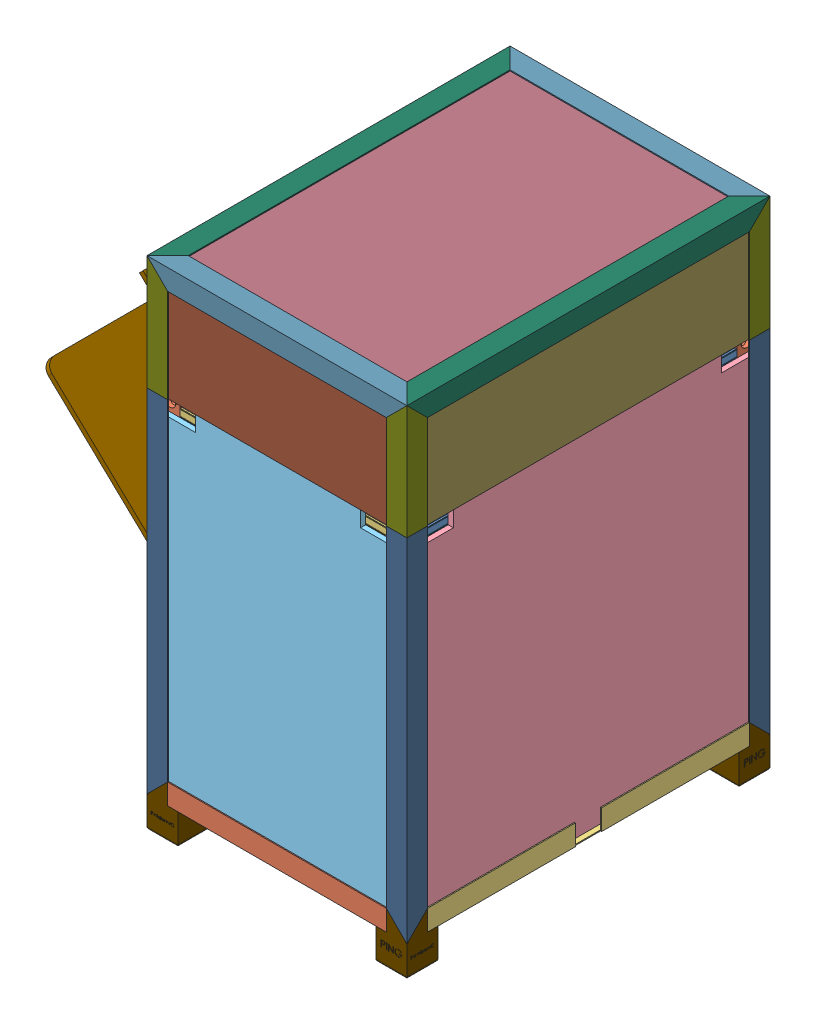
SolidWorks assembly carcasse, configuration Défaut. Lengths in mm.
Overall size (850.58 964 704).
62 component instances, 21 part files, 73 mates.
Components (placement in the parent):
- cadre_600x300mm-1: cadre_600x300mm [Défaut] at (-215.194 -19.8636 -400) size (480 40 680)
  - prof_40x40x600mm-1: prof_40x40x600mm [Défaut] at (-14.8937 4.0689 600) size (40 40 600)
  - Rexroth-Default-1: Rexroth-Default [Default] at (-14.8937 24.0689 720) x (0 -1 0) z (-1 0 0) size (40 40 40)
  - prof_40x40x600mm-3: prof_40x40x600mm [Défaut] at (425.1063 4.0689 600) size (40 40 600)
  - Rexroth-Default-3: Rexroth-Default [Default] at (-14.8937 24.0689 80) x (0 -1 0) z (0 0 -1) size (40 40 40)
  - Rexroth-Default-4: Rexroth-Default [Default] at (425.1063 24.0689 80) x (0 -1 0) z (1 0 0) size (40 40 40)
  - Rexroth-Default-5: Rexroth-Default [Default] at (425.1063 24.0689 720) x (0 -1 0) z (0 0 1) size (40 40 40)
  - prof_40x40x300mm-1: prof_40x40x300mm [Défaut] at (105.1063 4.0689 720) x (0 0 1) z (-1 0 0) size (40 40 400)
  - prof_40x40x300mm-2: prof_40x40x300mm [Défaut] at (105.1063 4.0689 80) x (0 0 1) z (-1 0 0) size (40 40 400)
- prof_40x40x600mm-1: prof_40x40x600mm [Défaut] at (209.9123 104.2053 -320) x (1 0 0) z (0 -1 0) size (40 40 600)
- prof_40x40x600mm-2: prof_40x40x600mm [Défaut] at (209.9123 104.2053 320) x (1 0 0) z (0 -1 0) size (40 40 600)
- prof_40x40x600mm-3: prof_40x40x600mm [Défaut] at (-230.0877 104.2053 320) x (1 0 0) z (0 -1 0) size (40 40 600)
- prof_40x40x600mm-4: prof_40x40x600mm [Défaut] at (-230.0877 104.2053 -320) x (1 0 0) z (0 -1 0) size (40 40 600)
- cadre_600x300mm-2: cadre_600x300mm [Défaut] at (195.0186 628.2742 -400) x (-1 0 0) z (0 0 1) size (480 40 680)
  - prof_40x40x600mm-1: prof_40x40x600mm [Défaut] at (-14.8937 4.0689 600) size (40 40 600)
  - Rexroth-Default-1: Rexroth-Default [Default] at (-14.8937 24.0689 720) x (0 -1 0) z (-1 0 0) size (40 40 40)
  - prof_40x40x600mm-3: prof_40x40x600mm [Défaut] at (425.1063 4.0689 600) size (40 40 600)
  - Rexroth-Default-3: Rexroth-Default [Default] at (-14.8937 24.0689 80) x (0 -1 0) z (0 0 -1) size (40 40 40)
  - Rexroth-Default-4: Rexroth-Default [Default] at (425.1063 24.0689 80) x (0 -1 0) z (1 0 0) size (40 40 40)
  - Rexroth-Default-5: Rexroth-Default [Default] at (425.1063 24.0689 720) x (0 -1 0) z (0 0 1) size (40 40 40)
  - prof_40x40x300mm-1: prof_40x40x300mm [Défaut] at (105.1063 4.0689 720) x (0 0 1) z (-1 0 0) size (40 40 400)
  - prof_40x40x300mm-2: prof_40x40x300mm [Défaut] at (105.1063 4.0689 80) x (0 0 1) z (-1 0 0) size (40 40 400)
- plaque_acrylique_680x670-2: plaque_acrylique_680x670 [Défaut] at (229.9123 299.2053 0) x (0 0 -1) z (1 0 0) size (680 670 10)
- plaque_acrylique_380x670-1: plaque_acrylique_380x670 [Défaut] at (39.9123 299.2053 -350) size (480 670 10)
- plaque_acrylique_380x670-2: plaque_acrylique_380x670 [Défaut] at (39.9123 299.2053 340) size (480 670 10)
- plaque_acrylique_680x670_porte-1: plaque_acrylique_680x670_porte [Défaut] at (-260.0877 299.2053 0) x (0 0 -1) z (1 0 0) size (680 670 10)
- charniere-1: charniere [Défaut] at (-253.7309 154.2053 256.2875) x (0 0 1) z (0 -1 0) size (40 29.08 53.23)
  - axe charnière-1: axe charnière [Défaut] at (-76.2875 9.8568 0) size (40 5 5)
  - batant charnière-1: batant charnière [Défaut] at (-76.2875 10.1991 -17.6196) size (40 7 33.5)
  - batant charnière-2: batant charnière [Défaut] at (-36.2875 -2.6626 12.4029) x (-1 0 0) z (0 0.723942 -0.689861) size (40 7 33.5)
- charniere-2: charniere [Défaut] at (-253.7309 154.2053 -143.7125) x (0 0 1) z (0 -1 0) size (40 29.08 53.23)
  - axe charnière-1: axe charnière [Défaut] at (-76.2875 9.8568 0) size (40 5 5)
  - batant charnière-1: batant charnière [Défaut] at (-76.2875 10.1991 -17.6196) size (40 7 33.5)
  - batant charnière-2: batant charnière [Défaut] at (-36.2875 -2.6626 12.4029) x (-1 0 0) z (0 0.723942 -0.689861) size (40 7 33.5)
- porte-1: porte [Défaut] at (-366.1448 256.769 0) x (0 0 -1) z (0.689861 0.723942 0) size (480 480 10)
- eclisse_40x40x670_bisote_x1-1: eclisse_40x40x670_bisote_x1 [Défaut] at (-242.0877 -47.7947 -331.8864) size (40 682 40)
- eclisse_40x40x670_bisote_x1-2: eclisse_40x40x670_bisote_x1 [Défaut] at (-241.9741 -47.7947 332) x (0 0 -1) z (1 0 0) size (40 682 40)
- eclisse_40x40x670_bisote_x1-3: eclisse_40x40x670_bisote_x1 [Défaut] at (221.9123 -47.7947 331.8864) x (-1 0 0) z (0 0 -1) size (40 682 40)
- eclisse_40x40x670_bisote_x1-4: eclisse_40x40x670_bisote_x1 [Défaut] at (221.7986 -47.7947 -332) x (0 0 1) z (-1 0 0) size (40 682 40)
- couvercle-1: couvercle [Défaut] at (227.4119 747.9268 345) size (504 222 704)
  - plaque_acrylique_380x210-1: plaque_acrylique_380x210 [Défaut] at (-187.4996 -8.7215 -5) size (480 210 10)
  - plaque_acrylique_680x210-1: plaque_acrylique_680x210 [Défaut] at (2.5004 -8.7215 -345) x (0 0 -1) z (1 0 0) size (680 210 10)
  - plaque_acrylique_680x210-2: plaque_acrylique_680x210 [Défaut] at (-487.4996 -8.7215 -345) x (0 0 -1) z (1 0 0) size (680 210 10)
  - plaque_acrylique_380x210-2: plaque_acrylique_380x210 [Défaut] at (-187.4996 -8.7215 -695) size (480 210 10)
  - plaque_acrylique_380x680-1: plaque_acrylique_380x680 [Défaut] at (-187.4996 96.2785 -345) x (1 0 0) z (0 1 0) size (480 680 10)
  - eclisse_40x40x404_bisote_x2-1: eclisse_40x40x404_bisote_x2 [Défaut] at (14.5004 88.1649 -677) x (0 0 1) z (0 -1 0) size (40 504 40)
  - eclisse_40x40x704_bisote_x2-1: eclisse_40x40x704_bisote_x2 [Défaut] at (-5.6132 88.2785 -697) x (0 -1 0) z (-1 0 0) size (40 704 40)
  - eclisse_40x40x404_bisote_x2-2: eclisse_40x40x404_bisote_x2 [Défaut] at (-489.4996 88.1649 -13) x (0 0 -1) z (0 -1 0) size (40 504 40)
  - eclisse_40x40x704_bisote_x2-2: eclisse_40x40x704_bisote_x2 [Défaut] at (-469.4996 88.1649 -697) x (1 0 0) z (0 -1 0) size (40 704 40)
  - eclisse_40x40x222_bisote_x1-1: eclisse_40x40x222_bisote_x1 [Défaut] at (-469.386 108.2785 -677) x (0 0 1) z (1 0 0) size (40 222 40)
  - eclisse_40x40x222_bisote_x1-2: eclisse_40x40x222_bisote_x1 [Défaut] at (-5.4996 108.2785 -676.8864) x (-1 0 0) z (0 0 1) size (40 222 40)
  - eclisse_40x40x222_bisote_x1-3: eclisse_40x40x222_bisote_x1 [Défaut] at (-5.6132 108.2785 -13) x (0 0 -1) z (-1 0 0) size (40 222 40)
  - eclisse_40x40x222_bisote_x1-4: eclisse_40x40x222_bisote_x1 [Défaut] at (-469.4996 108.2785 -13.1136) x (1 0 0) z (0 0 -1) size (40 222 40)
- plaque_acrylique_bas_380x680-1: plaque_acrylique_bas_380x680 [Défaut] at (39.9123 -35.7947 0) x (1 0 0) z (0 -1 0) size (480 680 10)
- Pied-1: Pied [Défaut] at (181.9123 -47.7947 -292) x (-1 0 0) z (0 -1 0) size (60 60 100)
- Pied-2: Pied [Défaut] at (181.9123 -47.7947 292) x (0 0 -1) z (0 -1 0) size (60 60 100)
- Pied-3: Pied [Défaut] at (-202.0877 -47.7947 292) x (1 0 0) z (0 -1 0) size (60 60 100)
- Pied-4: Pied [Défaut] at (-202.0877 -47.7947 -292) x (0 0 1) z (0 -1 0) size (60 60 100)
- eclisse_bas_40x40x704-2: eclisse_bas_40x40x704 [Défaut] at (-242.0877 -27.681 312) x (1 0 0) z (0 1 0) size (40 624 40)
- eclisse_bas_40x40x404-1: eclisse_bas_40x40x404 [Défaut] at (-222.0877 -27.681 -332) x (0 0 1) z (0 1 0) size (40 424 40)
- eclisse_bas_40x40x404-2: eclisse_bas_40x40x404 [Défaut] at (201.9123 -27.681 332) x (0 0 -1) z (0 1 0) size (40 424 40)
- eclisse_bas_support_Z_40x40x704-1: eclisse_bas_support_Z_40x40x704 [Défaut] at (221.7986 -27.7947 312) x (0 1 0) z (-1 0 0) size (40 624 40)
Mates (geometry in assembly coordinates):
- Coïncidente1: coincident anti-aligned: plane of cadre_600x300mm-1/Rexroth-Default-3 through (-230.0877 4.2053 -320) normal (0 1 0); plane of prof_40x40x600mm-4 through (-213.0877 4.2053 -337) normal (0 -1 0)
- Coïncidente2: coincident anti-aligned: plane of cadre_600x300mm-1/Rexroth-Default-1 through (-230.0877 4.2053 320) normal (0 1 0); plane of prof_40x40x600mm-3 through (-213.0877 4.2053 303) normal (0 -1 0)
- Coïncidente3: coincident anti-aligned: plane of cadre_600x300mm-1/Rexroth-Default-5 through (209.9123 4.2053 320) normal (0 1 0); plane of prof_40x40x600mm-2 through (226.9123 4.2053 303) normal (0 -1 0)
- Coïncidente4: coincident anti-aligned: plane of cadre_600x300mm-1/Rexroth-Default-4 through (209.9123 4.2053 -320) normal (0 1 0); plane of prof_40x40x600mm-1 through (226.9123 4.2053 -337) normal (0 -1 0)
- Coïncidente5: coincident aligned: plane of cadre_600x300mm-1/Rexroth-Default-4 through (229.9123 -15.7947 -320) normal (1 0 0); plane of prof_40x40x600mm-1 through (229.9123 604.2053 -314) normal (1 0 0)
- Coïncidente6: coincident aligned: plane of cadre_600x300mm-1/Rexroth-Default-4 through (209.9123 -15.7947 -340) normal (0 0 -1); plane of prof_40x40x600mm-1 through (215.9123 604.2053 -340) normal (0 0 -1)
- Coïncidente7: coincident aligned: plane of cadre_600x300mm-1/Rexroth-Default-5 through (229.9123 -15.7947 320) normal (1 0 0); plane of prof_40x40x600mm-2 through (229.9123 604.2053 303) normal (1 0 0)
- Coïncidente8: coincident aligned: plane of cadre_600x300mm-1/Rexroth-Default-5 through (209.9123 -15.7947 340) normal (0 0 1); plane of prof_40x40x600mm-2 through (226.9123 604.2053 340) normal (0 0 1)
- Coïncidente9: coincident aligned: plane of cadre_600x300mm-1/Rexroth-Default-1 through (-230.0877 -15.7947 340) normal (0 0 1); plane of prof_40x40x600mm-3 through (-213.0877 604.2053 340) normal (0 0 1)
- Coïncidente10: coincident aligned: plane of cadre_600x300mm-1/Rexroth-Default-1 through (-250.0877 -15.7947 320) normal (-1 0 0); plane of prof_40x40x600mm-3 through (-250.0877 604.2053 337) normal (-1 0 0)
- Coïncidente11: coincident aligned: plane of cadre_600x300mm-1/Rexroth-Default-3 through (-250.0877 -15.7947 -320) normal (-1 0 0); plane of prof_40x40x600mm-4 through (-250.0877 604.2053 -303) normal (-1 0 0)
- Coïncidente12: coincident aligned: plane of cadre_600x300mm-1/Rexroth-Default-3 through (-230.0877 -15.7947 -340) normal (0 0 -1); plane of prof_40x40x600mm-4 through (-247.0877 604.2053 -340) normal (0 0 -1)
- Coïncidente13: coincident anti-aligned: plane of prof_40x40x600mm-1 through (226.9123 604.2053 -337) normal (0 1 0); plane of cadre_600x300mm-2/Rexroth-Default-3 through (209.9123 604.2053 -320) normal (0 -1 0)
- Coïncidente14: coincident aligned: plane of prof_40x40x600mm-3 through (-250.0877 604.2053 337) normal (-1 0 0); plane of cadre_600x300mm-2/Rexroth-Default-5 through (-250.0877 624.2053 320) normal (-1 0 0)
- Coïncidente15: coincident aligned: plane of prof_40x40x600mm-3 through (-236.0877 604.2053 340) normal (0 0 1); plane of cadre_600x300mm-2/Rexroth-Default-5 through (-230.0877 624.2053 340) normal (0 0 1)
- Coïncidente38: coincident anti-aligned: plane of cadre_600x300mm-2/prof_40x40x600mm-1 through (229.9123 630.2053 -300) normal (1 0 0); plane of plaque_acrylique_680x670-2 through (229.9123 299.2053 0) normal (-1 0 0)
- Coïncidente39: coincident aligned: plane of prof_40x40x600mm-2 through (226.9123 604.2053 340) normal (0 0 1); plane of plaque_acrylique_680x670-2 through (239.9123 634.2053 340) normal (0 0 1)
- Coïncidente40: coincident aligned: plane of cadre_600x300mm-1/prof_40x40x600mm-3 through (215.9123 -35.7947 -300) normal (0 -1 0); plane of plaque_acrylique_680x670-2 through (239.9123 -35.7947 340) normal (0 -1 0)
- Coïncidente41: coincident anti-aligned: plane of prof_40x40x600mm-3 through (-213.0877 604.2053 340) normal (0 0 1); plane of plaque_acrylique_380x670-2 through (39.9123 299.2053 340) normal (0 0 -1)
- Coïncidente42: coincident aligned: plane of cadre_600x300mm-2/Rexroth-Default-5 through (-250.0877 624.2053 320) normal (-1 0 0); plane of plaque_acrylique_380x670-2 through (-250.0877 634.2053 350) normal (-1 0 0)
- Coïncidente43: coincident aligned: plane of cadre_600x300mm-1/prof_40x40x300mm-1 through (189.9123 -35.7947 326) normal (0 -1 0); plane of plaque_acrylique_380x670-2 through (-250.0877 -35.7947 350) normal (0 -1 0)
- Coïncidente44: coincident aligned: plane of cadre_600x300mm-1/prof_40x40x300mm-2 through (189.9123 -35.7947 -337) normal (0 -1 0); plane of plaque_acrylique_380x670-1 through (-250.0877 -35.7947 -340) normal (0 -1 0)
- Coïncidente45: coincident aligned: plane of cadre_600x300mm-2/Rexroth-Default-4 through (-250.0877 624.2053 -320) normal (-1 0 0); plane of plaque_acrylique_380x670-1 through (-250.0877 634.2053 -340) normal (-1 0 0)
- Coïncidente46: coincident anti-aligned: plane of prof_40x40x600mm-4 through (-247.0877 604.2053 -340) normal (0 0 -1); plane of plaque_acrylique_380x670-1 through (39.9123 299.2053 -340) normal (0 0 1)
- Coïncidente48: coincident aligned: plane of cadre_600x300mm-2/Rexroth-Default-5 through (-230.0877 624.2053 340) normal (0 0 1); plane of plaque_acrylique_680x670_porte-1 through (-250.0877 634.2053 340) normal (0 0 1)
- Coïncidente50: coincident anti-aligned: plane of plaque_acrylique_680x670_porte-1 through (-260.0877 299.2053 0) normal (-1 0 0); plane of charniere-1/batant charnière-1 through (-260.0877 114.2053 220) normal (1 0 0)
- Coïncidente51: coincident anti-aligned: plane of plaque_acrylique_680x670_porte-1 through (-260.0877 299.2053 0) normal (-1 0 0); plane of charniere-2/batant charnière-1 through (-260.0877 114.2053 -180) normal (1 0 0)
- Distance4: distance = 20 mm anti-aligned: plane of charniere-2/batant charnière-1 through (-263.5877 154.2053 -220) normal (0 0 -1); plane of plaque_acrylique_680x670_porte-1 through (-260.0877 574.2053 -240) normal (0 0 1)
- Coïncidente54: coincident aligned: line of plaque_acrylique_680x670_porte-1 through (-260.0877 154.2053 220) axis (0 0 -1); line of charniere-2/batant charnière-1 through (-260.0877 154.2053 -180) axis (0 0 -1)
- Distance5: distance = 20 mm anti-aligned: plane of plaque_acrylique_680x670_porte-1 through (-260.0877 574.2053 240) normal (0 0 -1); plane of charniere-1/batant charnière-1 through (-263.5877 154.2053 220) normal (0 0 1)
- Coïncidente57: coincident aligned: line of plaque_acrylique_680x670_porte-1 through (-260.0877 154.2053 220) axis (0 0 -1); line of charniere-1/batant charnière-1 through (-260.0877 154.2053 220) axis (0 0 -1)
- Coïncidente62: coincident anti-aligned: plane of charniere-1/batant charnière-2 through (-290.1309 184.3336 180) normal (0.689861 0.723942 0); plane of porte-1 through (-586.947 467.1766 30) normal (-0.689861 -0.723942 0)
- Coïncidente63: coincident anti-aligned: line of charniere-1/batant charnière-2 through (-261.1732 156.7391 200) axis (0 0 1); line of porte-1 through (-261.1732 156.7391 220) axis (0 0 -1)
- Coïncidente64: coincident anti-aligned: plane of plaque_acrylique_680x670_porte-1 through (-260.0877 574.2053 240) normal (0 0 -1); plane of porte-1 through (-558.3301 453.7202 240) normal (0 0 1)
- Coïncidente65: coincident anti-aligned: plane of plaque_acrylique_380x670-1 through (39.9123 299.2053 -350) normal (0 0 -1); plane of eclisse_40x40x670_bisote_x1-1 through (-260.0877 634.2053 -350) normal (0 0 1)
- Coïncidente66: coincident anti-aligned: plane of plaque_acrylique_680x670_porte-1 through (-260.0877 299.2053 0) normal (-1 0 0); plane of eclisse_40x40x670_bisote_x1-1 through (-260.0877 634.2053 -350) normal (1 0 0)
- Coïncidente67: coincident aligned: plane of plaque_acrylique_680x670_porte-1 through (-250.0877 634.2053 340) normal (0 1 0); plane of eclisse_40x40x670_bisote_x1-1 through (-242.0877 634.2053 -331.8864) normal (0 1 0)
- Coïncidente68: coincident anti-aligned: plane of plaque_acrylique_680x670-2 through (239.9123 299.2053 0) normal (1 0 0); plane of eclisse_40x40x670_bisote_x1-4 through (239.9123 634.2053 -350) normal (-1 0 0)
- Coïncidente69: coincident anti-aligned: plane of plaque_acrylique_380x670-1 through (39.9123 299.2053 -350) normal (0 0 -1); plane of eclisse_40x40x670_bisote_x1-4 through (239.9123 634.2053 -350) normal (0 0 1)
- Coïncidente70: coincident aligned: plane of plaque_acrylique_380x670-1 through (-250.0877 634.2053 -340) normal (0 1 0); plane of eclisse_40x40x670_bisote_x1-4 through (221.7986 634.2053 -332) normal (0 1 0)
- Coïncidente71: coincident anti-aligned: plane of plaque_acrylique_380x670-2 through (39.9123 299.2053 350) normal (0 0 1); plane of eclisse_40x40x670_bisote_x1-2 through (-260.0877 634.2053 350) normal (0 0 -1)
- Coïncidente72: coincident anti-aligned: plane of plaque_acrylique_680x670_porte-1 through (-260.0877 299.2053 0) normal (-1 0 0); plane of eclisse_40x40x670_bisote_x1-2 through (-260.0877 634.2053 350) normal (1 0 0)
- Coïncidente73: coincident aligned: plane of plaque_acrylique_380x670-2 through (-250.0877 634.2053 350) normal (0 1 0); plane of eclisse_40x40x670_bisote_x1-2 through (-241.9741 634.2053 332) normal (0 1 0)
- Coïncidente74: coincident anti-aligned: plane of plaque_acrylique_680x670-2 through (239.9123 299.2053 0) normal (1 0 0); plane of eclisse_40x40x670_bisote_x1-3 through (239.9123 634.2053 350) normal (-1 0 0)
- Coïncidente75: coincident anti-aligned: plane of plaque_acrylique_380x670-2 through (39.9123 299.2053 350) normal (0 0 1); plane of eclisse_40x40x670_bisote_x1-3 through (239.9123 634.2053 350) normal (0 0 -1)
- Coïncidente76: coincident aligned: plane of plaque_acrylique_380x670-2 through (-250.0877 634.2053 350) normal (0 1 0); plane of eclisse_40x40x670_bisote_x1-3 through (221.9123 634.2053 331.8864) normal (0 1 0)
- Coïncidente100: coincident: plane of plaque_acrylique_680x670_porte-1 through (-250.0877 634.2053 340) normal (0 1 0); line of eclisse_40x40x670_bisote_x1-2 through (-260.0877 634.2053 350) axis (0 0 -1)
- Coïncidente101: coincident anti-aligned: plane of prof_40x40x600mm-4 through (-250.0877 604.2053 -326) normal (-1 0 0); plane of plaque_acrylique_680x670_porte-1 through (-250.0877 299.2053 0) normal (1 0 0)
- Coïncidente116: coincident anti-aligned: line of plaque_acrylique_680x670-2 through (239.9123 634.2053 -260) axis (0 0 1); line of couvercle-1/plaque_acrylique_680x210-1 through (239.9123 634.2053 340) axis (0 0 -1)
- Coïncidente117: coincident anti-aligned: line of plaque_acrylique_380x670-1 through (149.9123 634.2053 -350) axis (-1 0 0); line of couvercle-1/plaque_acrylique_380x210-2 through (-250.0877 634.2053 -350) axis (1 0 0)
- Coïncidente118: coincident anti-aligned: plane of cadre_600x300mm-1/prof_40x40x600mm-1 through (-247.0877 -35.7947 -300) normal (0 -1 0); plane of plaque_acrylique_bas_380x680-1 through (39.9123 -35.7947 0) normal (0 1 0)
- Coïncidente119: coincident: plane of cadre_600x300mm-1/prof_40x40x600mm-1 through (-250.0877 -21.7947 -300) normal (-1 0 0); line of plaque_acrylique_bas_380x680-1 through (-250.0877 -35.7947 340) axis (0 0 -1)
- Coïncidente120: coincident: line of cadre_600x300mm-1/prof_40x40x300mm-2 through (189.9123 -32.7947 -340) axis (-1 0 0); plane of plaque_acrylique_bas_380x680-1 through (-250.0877 -45.7947 -340) normal (0 0 -1)
- Coaxiale1: concentric aligned: cylinder of plaque_acrylique_bas_380x680-1 through (209.9123 -35.7947 -320) axis (0 -1 0) radius 12.5; cylinder of Pied-1 through (209.9123 -27.7947 -320) axis (0 -1 0) radius 12
- Coïncidente124: coincident anti-aligned: plane of eclisse_40x40x670_bisote_x1-4 through (-348.0877 -47.7947 -352) normal (0 -0.707107 0.707107); plane of Pied-1 through (239.9123 -7.7947 -312) normal (0 0.707107 -0.707107)
- Coaxiale2: concentric aligned: circle of plaque_acrylique_bas_380x680-1; cylinder of Pied-2 through (209.9123 -27.7947 320) axis (0 -1 0) radius 12
- Coïncidente126: coincident anti-aligned: plane of eclisse_40x40x670_bisote_x1-3 through (241.9123 -47.7947 -238) normal (-0.707107 -0.707107 0); plane of Pied-2 through (201.9123 -7.7947 350) normal (0.707107 0.707107 0)
- Coaxiale3: concentric aligned: circle of plaque_acrylique_bas_380x680-1; cylinder of Pied-3 through (-230.0877 -27.7947 320) axis (0 -1 0) radius 12
- Coïncidente130: coincident anti-aligned: plane of eclisse_40x40x670_bisote_x1-2 through (327.9123 -47.7947 352) normal (0 -0.707107 -0.707107); plane of Pied-3 through (-260.0877 -7.7947 312) normal (0 0.707107 0.707107)
- Coaxiale4: concentric aligned: circle of plaque_acrylique_bas_380x680-1; cylinder of Pied-4 through (-230.0877 -27.7947 -320) axis (0 -1 0) radius 12
- Coïncidente131: coincident anti-aligned: plane of eclisse_40x40x670_bisote_x1-1 through (-262.0877 -47.7947 238) normal (0.707107 -0.707107 0); plane of Pied-4 through (-222.0877 -7.7947 -350) normal (-0.707107 0.707107 0)
- Coïncidente132: coincident anti-aligned: plane of plaque_acrylique_680x670_porte-1 through (-260.0877 299.2053 0) normal (-1 0 0); plane of eclisse_bas_40x40x704-2 through (-260.0877 -45.7947 -312) normal (1 0 0)
- Coïncidente133: coincident anti-aligned: plane of plaque_acrylique_bas_380x680-1 through (39.9123 -45.7947 0) normal (0 -1 0); plane of eclisse_bas_40x40x704-2 through (-260.0877 -45.7947 -312) normal (0 1 0)
- Coïncidente134: coincident anti-aligned: line of eclisse_40x40x670_bisote_x1-2 through (-262.0877 634.2053 312) axis (0 -1 0); line of eclisse_bas_40x40x704-2 through (-262.0877 -47.7947 312) axis (0 1 0)
- Coïncidente135: coincident anti-aligned: plane of plaque_acrylique_380x670-1 through (39.9123 299.2053 -350) normal (0 0 -1); plane of eclisse_bas_40x40x404-1 through (201.9123 -45.7947 -350) normal (0 0 1)
- Coïncidente136: coincident anti-aligned: plane of plaque_acrylique_bas_380x680-1 through (39.9123 -45.7947 0) normal (0 -1 0); plane of eclisse_bas_40x40x404-1 through (201.9123 -45.7947 -350) normal (0 1 0)
- Coïncidente137: coincident anti-aligned: line of Pied-1 through (201.9123 -7.7947 -352) axis (0 -1 0); line of eclisse_bas_40x40x404-1 through (201.9123 -47.7947 -352) axis (0 1 0)
- Coïncidente138: coincident anti-aligned: plane of plaque_acrylique_380x670-2 through (39.9123 299.2053 350) normal (0 0 1); plane of eclisse_bas_40x40x404-2 through (-222.0877 -45.7947 350) normal (0 0 -1)
- Coïncidente139: coincident anti-aligned: plane of plaque_acrylique_bas_380x680-1 through (39.9123 -45.7947 0) normal (0 -1 0); plane of eclisse_bas_40x40x404-2 through (-222.0877 -45.7947 350) normal (0 1 0)
- Coïncidente140: coincident anti-aligned: line of Pied-3 through (-222.0877 -7.7947 352) axis (0 -1 0); line of eclisse_bas_40x40x404-2 through (-222.0877 -47.7947 352) axis (0 1 0)
- Coïncidente142: coincident anti-aligned: plane of plaque_acrylique_680x670-2 through (239.9123 299.2053 0) normal (1 0 0); plane of eclisse_bas_support_Z_40x40x704-1 through (239.9123 -45.7947 -312) normal (-1 0 0)
- Coïncidente143: coincident anti-aligned: plane of plaque_acrylique_bas_380x680-1 through (39.9123 -45.7947 0) normal (0 -1 0); plane of eclisse_bas_support_Z_40x40x704-1 through (239.9123 -45.7947 -312) normal (0 1 0)
- Coïncidente144: coincident anti-aligned: plane of Pied-2 through (239.9123 -7.7947 312) normal (0 0 -1); plane of eclisse_bas_support_Z_40x40x704-1 through (221.7986 -27.7947 312) normal (0 0 1)
